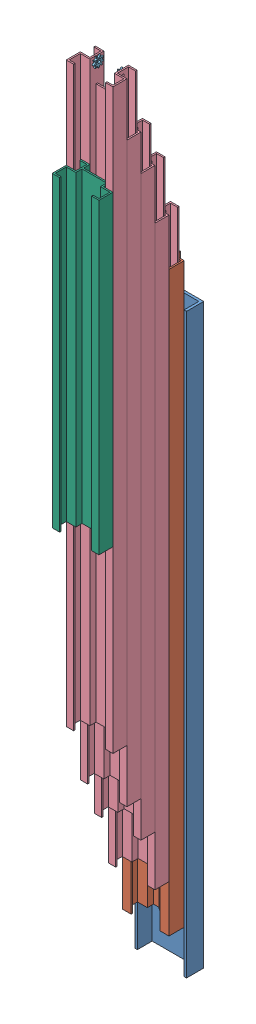
SolidWorks assembly 04, configuration Default. Lengths in mm.
Overall size (210 3282.37 416.58).
16 component instances, 6 part files, 26 mates.
Components (placement in the parent):
- Part2-1: Part2 [Default] at (977.9066 -10.8653 1777.8241) size (210 2350 70)
- Part1-1: Part1 [Default] at (1072.9066 162.8694 1833.4072) size (190 2350 87)
- Part5-1: Part5 [Default] at (1072.9066 1065.8987 1741.8241) x (0.488393 0 0.872624) z (0 1 0) size (48 48 500)
- Part3-1: Part3 [Default] at (1072.9066 354.2807 1890.4072) size (190 2350 108)
- Part3-2: Part3 [Default] at (1072.9066 557.6795 1947.4072) size (190 2350 108)
- Part3-4: Part3 [Default] at (1072.9066 704.0726 2004.4072) size (190 2350 108)
- Part4-1: Part4 [Default] at (1024.0069 2887.6795 1873.9072) x (1 0 0) z (0 -0.928456 0.371443) size (9.5 43.8 44.47)
- Part4-2: Part4 [Default] at (1114.5064 2887.6795 1873.9072) size (9.5 43.8 44.47)
- Part4-4: Part4 [Default] at (1114.5064 3034.0726 1930.9072) size (9.5 43.8 44.47)
- Part4-5: Part4 [Default] at (1114.5064 2684.2807 1816.9072) size (9.5 43.8 44.47)
- Part4-6: Part4 [Default] at (1024.0069 3034.0726 1930.9072) size (9.5 43.8 44.47)
- Part4-7: Part4 [Default] at (1024.0069 2684.2807 1816.9072) size (9.5 43.8 44.47)
- Part3-5: Part3 [Default] at (1072.9066 920.2325 2061.4072) size (190 2350 108)
- Part4-9: Part4 [Default] at (1024.0069 3250.2325 1987.9072) size (9.5 43.8 44.47)
- Part4-10: Part4 [Default] at (1114.5064 3250.2325 1987.9072) size (9.5 43.8 44.47)
- Part3 - Copy-1: Part3 - Copy [Default] at (1072.9066 1648.9252 2118.4072) size (190 1550 108)
Mates (geometry in assembly coordinates):
- Parallel1: parallel aligned: plane of Part2-1 through (977.9066 2339.1347 1777.8241) normal (0 1 0); plane of Part1-1 through (1072.9066 2512.8694 1741.8241) normal (0 1 0)
- Concentric2: concentric anti-aligned: cylinder of Part1-1 through (1072.9066 162.8694 1741.8241) axis (0 1 0) radius 24; cylinder of Part5-1 through (1072.9066 1565.8987 1741.8241) axis (0 -1 0) radius 24
- Tangent2: tangent aligned: cylinder of Part1-1 through (1072.9066 162.8694 1741.8241) axis (0 1 0) radius 24; cylinder of Part5-1 through (1072.9066 1565.8987 1741.8241) axis (0 -1 0) radius 24
- Tangent3: tangent anti-aligned: plane of Part2-1 through (977.9066 -10.8653 1717.8241) normal (0 0 1); cylinder of Part5-1 through (1072.9066 1565.8987 1741.8241) axis (0 -1 0) radius 24
- Coincident3: coincident anti-aligned: plane of Part2-1 through (977.9066 -10.8653 1777.8241) normal (1 0 0); plane of Part1-1 through (977.9066 162.8694 1777.4072) normal (-1 0 0)
- Coincident10: coincident anti-aligned: plane of Part1-1 through (977.9066 162.8694 1839.4072) normal (0 0 1); plane of Part3-1 through (977.9066 354.2807 1839.4072) normal (0 0 -1)
- Coincident11: coincident anti-aligned: plane of Part1-1 through (1131.9066 162.8694 1839.4072) normal (0 0 1); plane of Part3-1 through (1167.9066 2704.2807 1839.4072) normal (0 0 -1)
- Parallel6: parallel aligned: plane of Part1-1 through (1167.9066 162.8694 1839.4072) normal (1 0 0); plane of Part3-1 through (1167.9066 2704.2807 1845.4072) normal (1 0 0)
- Coincident13: coincident anti-aligned: line of Part1-1 through (1167.9066 162.8694 1839.4072) axis (0 1 0); line of Part3-1 through (1167.9066 2704.2807 1839.4072) axis (0 -1 0)
- Coincident14: coincident anti-aligned: plane of Part3-1 through (1072.9066 354.2807 1896.4072) normal (0 0 1); plane of Part3-2 through (1167.9066 2907.6795 1896.4072) normal (0 0 -1)
- Coincident15: coincident anti-aligned: line of Part3-1 through (1167.9066 354.2807 1896.4072) axis (0 1 0); line of Part3-2 through (1167.9066 2907.6795 1896.4072) axis (0 -1 0)
- Coincident25: coincident anti-aligned: circle of Part3-2; circle of Part4-2
- Coincident26: coincident anti-aligned: circle of Part3-2; circle of Part4-1
- Coincident28: coincident anti-aligned: circle of Part3-1; circle of Part4-5
- Coincident29: coincident anti-aligned: circle of Part3-4; circle of Part4-4
- Coincident30: coincident anti-aligned: circle of Part3-1; circle of Part4-7
- Coincident32: coincident anti-aligned: circle of Part3-4; circle of Part4-6
- Coincident33: coincident anti-aligned: line of Part3-4 through (1167.9066 704.0726 2010.4072) axis (0 1 0); line of Part3-5 through (1167.9066 3270.2325 2010.4072) axis (0 -1 0)
- Coincident34: coincident anti-aligned: plane of Part3-4 through (1072.9066 704.0726 2010.4072) normal (0 0 1); plane of Part3-5 through (1167.9066 3270.2325 2010.4072) normal (0 0 -1)
- Coincident36: coincident anti-aligned: circle of Part3-5; circle of Part4-9
- Coincident37: coincident anti-aligned: circle of Part3-5; circle of Part4-10
- Coincident38: coincident anti-aligned: plane of Part3-5 through (1072.9066 920.2325 2016.4072) normal (0 0 1); plane of Part3 - Copy-1 through (1072.9066 1648.9252 2016.4072) normal (0 0 -1)
- Coincident40: coincident anti-aligned: line of Part3-4 through (1167.9066 704.0726 2010.4072) axis (0 1 0); line of Part3-5 through (1167.9066 3270.2325 2010.4072) axis (0 -1 0)
- Coincident41: coincident anti-aligned: line of Part3-5 through (1167.9066 920.2325 2067.4072) axis (0 1 0); line of Part3 - Copy-1 through (1167.9066 3198.9252 2067.4072) axis (0 -1 0)
- Coincident42: coincident anti-aligned: plane of Part3-2 through (1072.9066 557.6795 1902.4072) normal (0 0 1); plane of Part3-4 through (1072.9066 704.0726 1902.4072) normal (0 0 -1)
- Coincident43: coincident anti-aligned: line of Part3-2 through (977.9066 2907.6795 1953.4072) axis (0 -1 0); line of Part3-4 through (977.9066 704.0726 1953.4072) axis (0 1 0)
